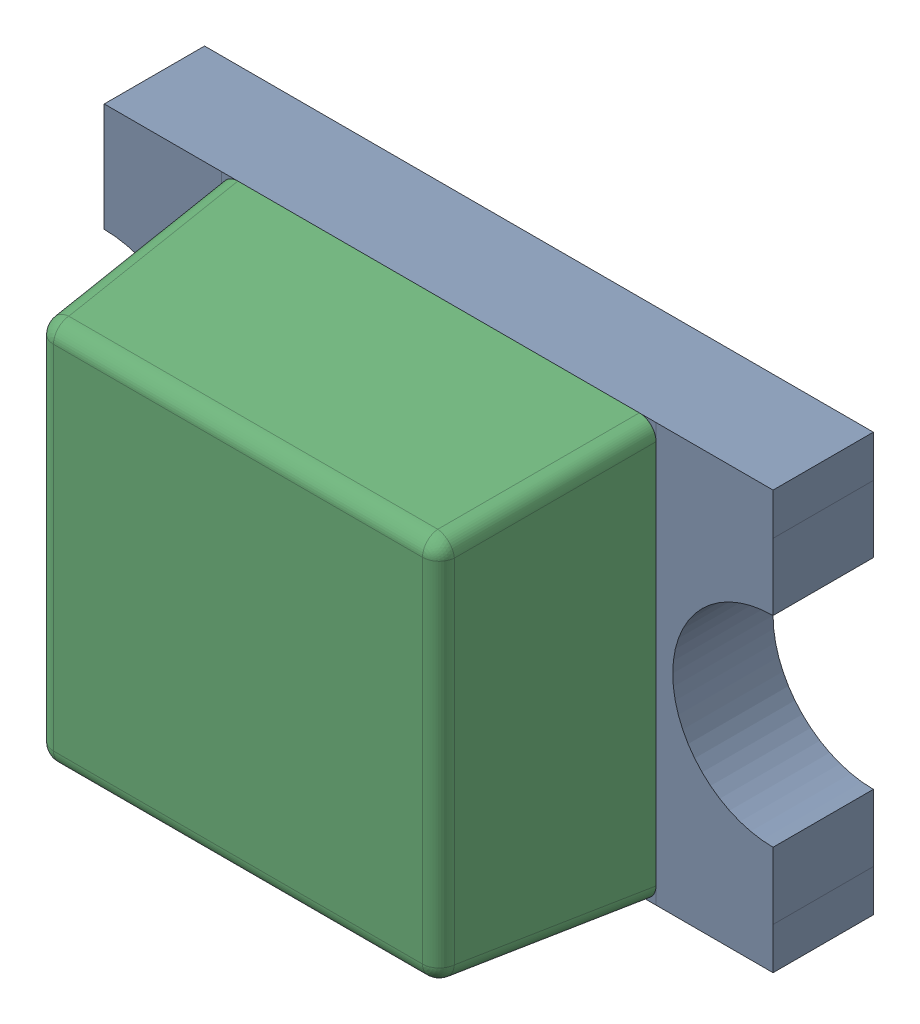
SolidWorks assembly D4_1.step, configuration Default. Lengths in mm.
Overall size (2 1.25 0.9).
2 component instances, 2 part files, 0 mates.
Components (placement in the parent):
- LED 0805 Base RED_1.step-3: LED 0805 Base RED_1.step [Default] at (506.9841 335.28 0) x (1 0 0) z (0 -1 0) size (2 0.4 1.25)
- LED 0805 Lens RED_1.step-3: LED 0805 Lens RED_1.step [Default] at (506.9841 335.28 0) x (1 0 0) z (0 -1 0) size (1.3 0.6 1.25)
